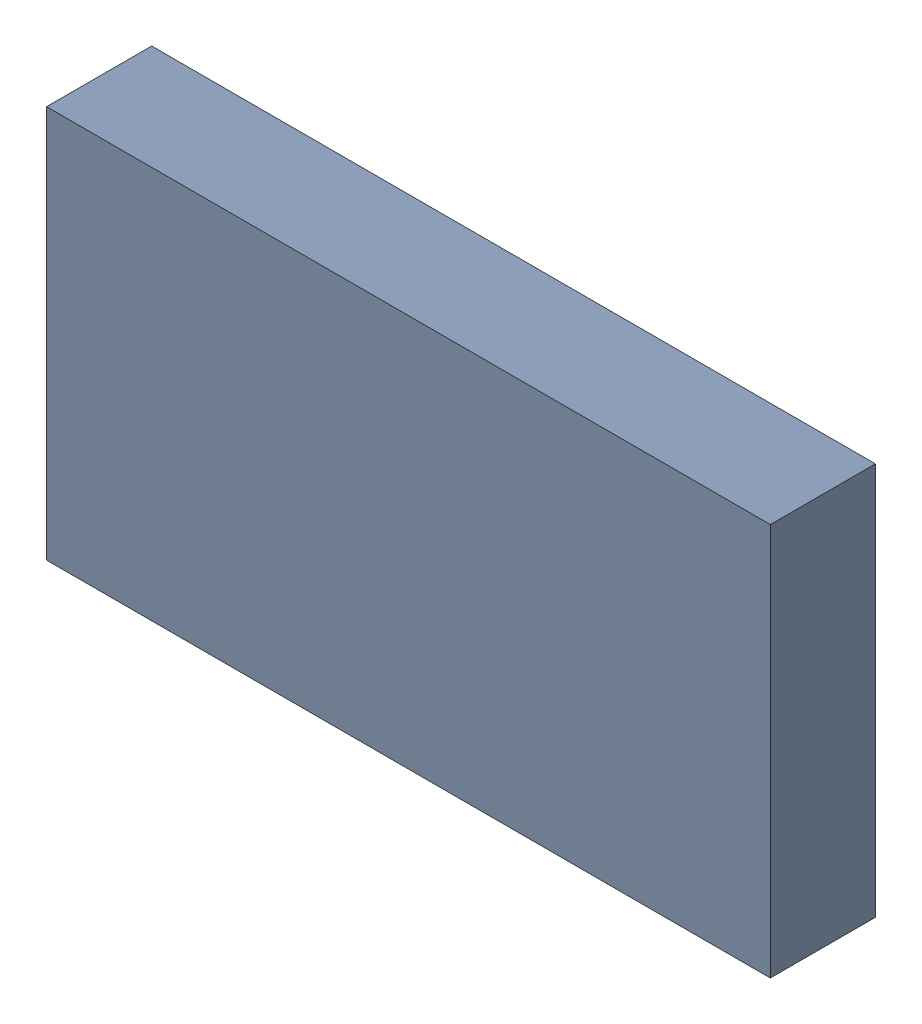
SolidWorks assembly 6327399232, configuration Default. Lengths in mm.
Overall size (1.75 0.95 0.25).
2 component instances, 1 part files, 0 mates.
Components (placement in the parent):
- 6701982208-1:  [Default] at (27.7 14.8 0) (suppressed, hidden)
- Extruded-8-1: Extruded-8 [Default] at origin size (1.75 0.95 0.25)
